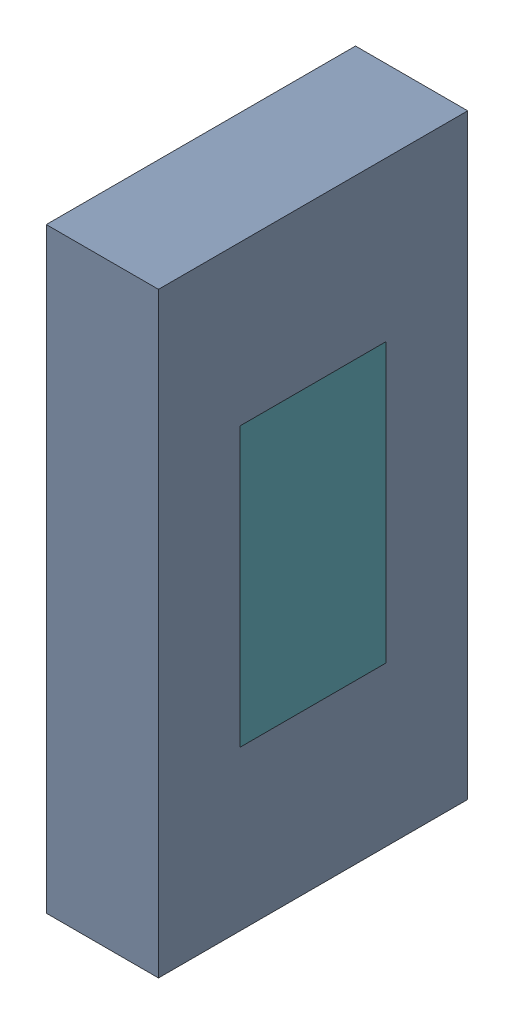
SolidWorks assembly C7, configuration Default. Lengths in mm.
Overall size (0.33 1.35 0.7).
25 component instances, 7 part files, 0 mates.
Components (placement in the parent):
- 6701982208-1:  [Default] at (27.7 14.8 0) (suppressed, hidden)
- 6327397120-1: 6327397120 [Default] at (4.2287 10.45 -3.3931) x (0 0 -1) z (1 0 0) size (0.7 1.35 0.25)
  - 6701982208-1:  [Default] at (27.7 14.8 0) (suppressed, hidden)
  - Extruded-1: Extruded [Default] at origin size (0.7 1.35 0.25)
- 6327396544-1: 6327396544 [Default] at (4.2287 10.45 -3.3931) x (0 0 -1) z (1 0 0) size (0.33 0.63 0.25)
  - 6701982208-1:  [Default] at (27.7 14.8 0) (suppressed, hidden)
  - Extruded-1-1: Extruded-1 [Default] at origin size (0.33 0.63 0.25)
- 6327396736-1: 6327396736 [Default] at (4.2287 10.45 -3.3931) x (0 0 -1) z (1 0 0) size (0.43 0.73 0.25)
  - 6701982208-1:  [Default] at (27.7 14.8 0) (suppressed, hidden)
  - Extruded-2-1: Extruded-2 [Default] at origin size (0.43 0.73 0.25)
- 6327396928-1: 6327396928 [Default] at (4.2287 10.45 -3.3931) x (0 0 -1) z (1 0 0) size (0.6 1.25 0.25)
  - 6701982208-1:  [Default] at (27.7 14.8 0) (suppressed, hidden)
  - Extruded-3-1: Extruded-3 [Default] at origin size (0.6 1.25 0.25)
- 6327397120-2: 6327397120 [Default] at (4.2287 10.45 -3.3931) x (0 0 -1) z (1 0 0) size (0.7 1.35 0.25)
  - 6701982208-1:  [Default] at (27.7 14.8 0) (suppressed, hidden)
  - Extruded-1: Extruded [Default] at origin size (0.7 1.35 0.25)
- 6327397312-1: 6327397312 [Default] at (4.2287 10.45 -3.3931) x (0 0 -1) z (1 0 0) size (0.5 1.15 0.25)
  - 6701982208-1:  [Default] at (27.7 14.8 0) (suppressed, hidden)
  - Extruded-4-1: Extruded-4 [Default] at origin size (0.5 1.15 0.25)
- 6327397504-1: 6327397504 [Default] at (4.1527 10.45 -3.3931) x (0 0 -1) z (1 0 0) size (0.33 0.63 0.33)
  - 6701982208-1:  [Default] at (27.7 14.8 0) (suppressed, hidden)
  - Extruded-5-1: Extruded-5 [Default] at origin size (0.33 0.63 0.33)
- 6327400768-1: 6327400768 [Default] at (4.2287 10.45 -3.3931) x (0 0 -1) z (1 0 0) size (0.33 0.33 0.25)
  - 6701982208-1:  [Default] at (27.7 14.8 0) (suppressed, hidden)
  - Extruded-6-1: Extruded-6 [Default] at origin size (0.33 0.33 0.25)
